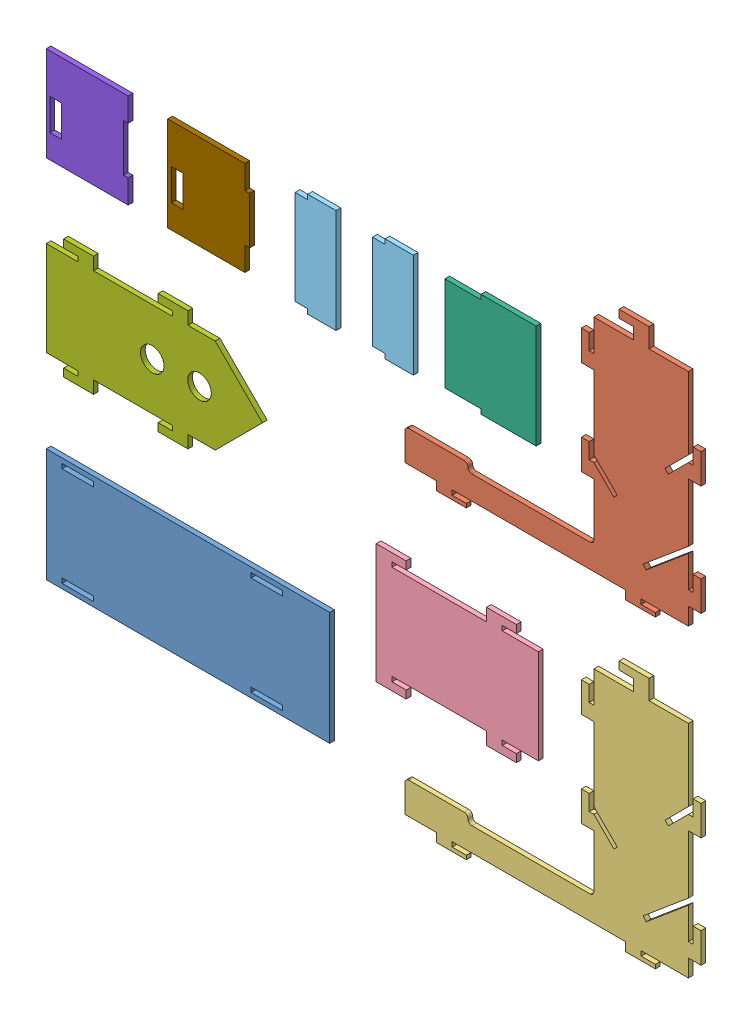
SolidWorks assembly 装配体1, configuration 默认. Lengths in mm.
Overall size (500 400 60.12).
10 component instances, 9 part files, 16 mates.
Components (placement in the parent):
- 凸台-拉伸5-2: 凸台-拉伸5 [默认] at (82.2645 -85.4603 -37.3689) x (1 0 0) z (0 -1 0) size (180 3 72)
- 切除-拉伸1[1]-1: 切除-拉伸1[1] [默认] at (310.0105 89.8521 25.6311) size (188 157.8 3)
- 切除-拉伸1[2]-1: 切除-拉伸1[2] [默认] at (310.0105 -103.5946 -37.3689) size (188 157.8 3)
- 凸台-拉伸7-1: 凸台-拉伸7 [默认] at (211.7725 31.1692 -37.3689) x (0 0 -1) z (0 1 0) size (3 103 76)
- 凸台-拉伸8-1: 凸台-拉伸8 [默认] at (71.7214 140.548 -104.0085) x (0.707107 0 -0.707107) z (0 -1 0) size (20.51 20.51 66)
- 凸台-拉伸8-2: 凸台-拉伸8 [默认] at (22.6472 140.548 -104.0085) x (0.707107 0 -0.707107) z (0 -1 0) size (20.51 20.51 66)
- 凸台-拉伸11-1: 凸台-拉伸11 [默认] at (187.6068 140.548 -71.0107) x (0.766044 0 -0.642788) z (0 -1 0) size (46.36 39.58 66)
- 凸台-拉伸12-1: 凸台-拉伸12 [默认] at (-137.7355 33.454 -100.3689) x (0 0 -1) z (0 -1 0) size (3 137.3 76)
- 凸台-拉伸13-1: 凸台-拉伸13 [默认] at (-194.4401 143.548 -139.3639) x (0 -1 0) z (-0.707107 0 0.707107) size (60 38.89 38.89)
- 凸台-拉伸14-1: 凸台-拉伸14 [默认] at (-70.6113 143.548 108.2951) x (0 -1 0) z (0.707107 0 0.707107) size (60 38.89 38.89)
Mates (geometry in assembly coordinates):
- 重合2: coincident aligned: plane of 切除-拉伸1[1]-1 through (310.0105 133.7683 -40.3689) normal (1 0 0); plane of 切除-拉伸1[2]-1 through (310.0105 -9.3519 -103.3689) normal (1 0 0)
- 重合4: coincident aligned: plane of 凸台-拉伸11-1 through (178.3183 206.548 -37.3689) normal (0 1 0); plane of 凸台-拉伸8-1 through (117.361 206.548 -37.3689) normal (0 1 0)
- 重合5: coincident aligned: plane of 凸台-拉伸8-1 through (117.361 206.548 -37.3689) normal (0 1 0); plane of 凸台-拉伸8-2 through (68.2869 206.548 -37.3689) normal (0 1 0)
- 重合6: coincident aligned: plane of 凸台-拉伸13-1 through (-45.7355 203.548 -37.3689) normal (0 1 0); plane of 凸台-拉伸14-1 through (28.3836 203.548 -40.3689) normal (0 1 0)
- 重合7: coincident aligned: plane of 凸台-拉伸13-1 through (-194.4401 143.548 -37.3689) normal (0 0 1); plane of 凸台-拉伸14-1 through (-70.6113 143.548 -37.3689) normal (0 0 1)
- 重合8: coincident aligned: plane of 凸台-拉伸11-1 through (187.6068 140.548 -37.3689) normal (0 0 1); plane of 凸台-拉伸13-1 through (-194.4401 143.548 -37.3689) normal (0 0 1)
- 重合9: coincident aligned: plane of 凸台-拉伸8-1 through (71.7214 140.548 -37.3689) normal (0 0 1); plane of 凸台-拉伸13-1 through (-194.4401 143.548 -37.3689) normal (0 0 1)
- 重合10: coincident aligned: plane of 凸台-拉伸8-2 through (22.6472 140.548 -37.3689) normal (0 0 1); plane of 凸台-拉伸13-1 through (-194.4401 143.548 -37.3689) normal (0 0 1)
- 重合11: coincident aligned: plane of 切除-拉伸1[1]-1 through (130.0105 256.9309 -37.3689) normal (0 0 1); plane of 凸台-拉伸13-1 through (-194.4401 143.548 -37.3689) normal (0 0 1)
- 重合12: coincident aligned: plane of 凸台-拉伸7-1 through (211.7725 31.1692 -37.3689) normal (0 0 1); plane of 凸台-拉伸13-1 through (-194.4401 143.548 -37.3689) normal (0 0 1)
- 重合13: coincident aligned: plane of 切除-拉伸1[2]-1 through (247.5105 -86.0946 -37.3689) normal (0 0 1); plane of 凸台-拉伸13-1 through (-194.4401 143.548 -37.3689) normal (0 0 1)
- 重合14: coincident aligned: plane of 凸台-拉伸5-2 through (82.2645 -85.4603 -37.3689) normal (0 0 1); plane of 凸台-拉伸13-1 through (-194.4401 143.548 -37.3689) normal (0 0 1)
- 重合15: coincident aligned: plane of 凸台-拉伸12-1 through (-137.7355 33.454 -37.3689) normal (0 0 1); plane of 凸台-拉伸13-1 through (-194.4401 143.548 -37.3689) normal (0 0 1)
- 重合18: coincident aligned: plane of 凸台-拉伸5-2 through (-97.7355 -88.4603 -40.3689) normal (-1 0 0); plane of 凸台-拉伸12-1 through (-97.7355 96.454 -37.3689) normal (-1 0 0)
- 重合19: coincident aligned: plane of 凸台-拉伸12-1 through (-97.7355 96.454 -37.3689) normal (-1 0 0); plane of 凸台-拉伸13-1 through (-97.7355 203.548 -37.3689) normal (-1 0 0)
- 重合20: coincident aligned: plane of 凸台-拉伸8-2 through (68.2869 203.548 -37.3689) normal (0 1 0); plane of 凸台-拉伸14-1 through (28.3836 203.548 -40.3689) normal (0 1 0)
